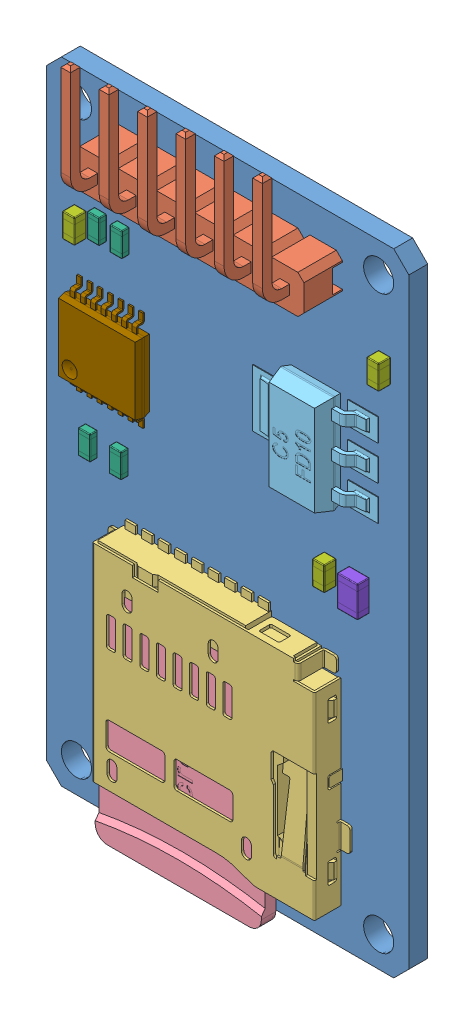
SolidWorks assembly Product_TF Micro SD Card Memory Modul Arduino, configuration Default. Lengths in mm.
Overall size (24 45.73 7.3).
19 component instances, 9 part files, 0 mates.
Components (placement in the parent):
- PCB-1: PCB [По умолчанию] at origin size (24 41.8 1.25)
- 1 Pin 2.54 mm Right Angle Single Row Pin Header Male 90 degrees Needle Connector-1: 1 Pin 2.54 mm Right Angle Single Row Pin Header Male 90 degrees Needle Connector [По умолчанию] at (-6.375 38.55 -1.71) x (0 1 0) z (0 0 1) size (8.45 2.54 7.3)
- 1 Pin 2.54 mm Right Angle Single Row Pin Header Male 90 degrees Needle Connector-2: 1 Pin 2.54 mm Right Angle Single Row Pin Header Male 90 degrees Needle Connector [По умолчанию] at (-3.835 38.55 -1.71) x (0 1 0) z (0 0 1) size (8.45 2.54 7.3)
- 1 Pin 2.54 mm Right Angle Single Row Pin Header Male 90 degrees Needle Connector-3: 1 Pin 2.54 mm Right Angle Single Row Pin Header Male 90 degrees Needle Connector [По умолчанию] at (-1.295 38.55 -1.71) x (0 1 0) z (0 0 1) size (8.45 2.54 7.3)
- 1 Pin 2.54 mm Right Angle Single Row Pin Header Male 90 degrees Needle Connector-4: 1 Pin 2.54 mm Right Angle Single Row Pin Header Male 90 degrees Needle Connector [По умолчанию] at (1.245 38.55 -1.71) x (0 1 0) z (0 0 1) size (8.45 2.54 7.3)
- 1 Pin 2.54 mm Right Angle Single Row Pin Header Male 90 degrees Needle Connector-5: 1 Pin 2.54 mm Right Angle Single Row Pin Header Male 90 degrees Needle Connector [По умолчанию] at (3.785 38.55 -1.71) x (0 1 0) z (0 0 1) size (8.45 2.54 7.3)
- 1 Pin 2.54 mm Right Angle Single Row Pin Header Male 90 degrees Needle Connector-6: 1 Pin 2.54 mm Right Angle Single Row Pin Header Male 90 degrees Needle Connector [По умолчанию] at (6.325 38.55 -1.71) x (0 1 0) z (0 0 1) size (8.45 2.54 7.3)
- slot-1: slot [По умолчанию] at (-0.1 9.44 2.1) size (16 15 2.44)
- sd-1: sd [По умолчанию] at (-45.7851 11.4225 2.13) size (11 15 1.1)
- nano - reg-1: nano - reg [По умолчанию] at (5.85 28.63 1.25) x (0 -1 0) z (-1 0 0) size (6.5 1.69 8.3)
- res_603-1: res_603 [По умолчанию] at (-9.4 21.6 1.25) x (0 -1 0) z (-1 0 0) size (1.6 0.5 0.8)
- res_603-2: res_603 [По умолчанию] at (-7.35 21.6 1.25) x (0 -1 0) z (-1 0 0) size (1.6 0.5 0.8)
- res_603-3: res_603 [По умолчанию] at (-7.3 34.3 1.25) x (0 -1 0) z (-1 0 0) size (1.6 0.5 0.8)
- res_603-4: res_603 [По умолчанию] at (-8.8 34.3 1.25) x (0 -1 0) z (-1 0 0) size (1.6 0.5 0.8)
- cap_603-1: cap_603 [По умолчанию] at (-9.34 32.2 2.05) x (0 1 0) z (0 0 1) size (1.6 0.8 0.8)
- cap_603-2: cap_603 [По умолчанию] at (7.2 20.55 2.05) x (0 1 0) z (0 0 1) size (1.6 0.8 0.8)
- cap_603-3: cap_603 [По умолчанию] at (10.8 33.9 2.05) x (0 1 0) z (0 0 1) size (1.6 0.8 0.8)
- cap_805-1: cap_805 [По умолчанию] at (9.4 20.1 2.05) x (0 1 0) z (0 0 1) size (2.06 1.35 0.82)
- LVC125A-1: LVC125A [По умолчанию] at (-10.3 28.9 1.25) x (0 -1 0) z (0 0 1) size (6.6 5.2 0.95)
